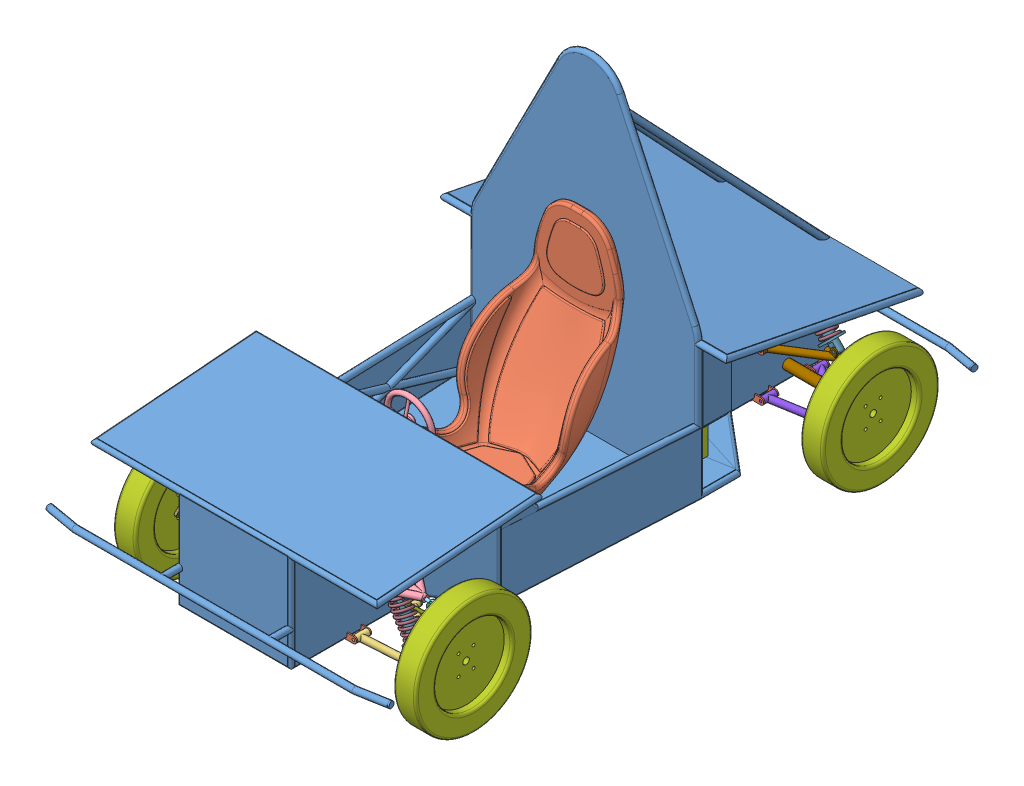
SolidWorks assembly Design report assembly, configuration Default. Lengths in mm.
Overall size (1371.98 1545.67 2400.3).
109 component instances, 30 part files, 125 mates.
Components (placement in the parent):
- RollCage with bodyworks-1: RollCage with bodyworks [Default<As Machined>] at (132.5653 649.3406 2655.1235) size (1371.98 1337.56 2400.3)
- wishbone mount-1: wishbone mount [Default] at (348.4653 649.3406 2441.8435) size (52.7 25.4 5)
- wishbone mount-2: wishbone mount [Default] at (348.4653 649.3406 2386.2135) size (52.7 25.4 5)
- wishbone mount-3: wishbone mount [Default] at (348.4653 649.3406 2238.6435) size (52.7 25.4 5)
- wishbone mount-4: wishbone mount [Default] at (348.4653 649.3406 2183.0135) size (52.7 25.4 5)
- wishbone mount-5: wishbone mount [Default] at (348.4653 830.0606 2441.8435) size (52.7 25.4 5)
- wishbone mount-6: wishbone mount [Default] at (348.4653 830.0606 2386.2135) size (52.7 25.4 5)
- wishbone mount-7: wishbone mount [Default] at (348.4653 830.0606 2238.6435) size (52.7 25.4 5)
- wishbone mount-8: wishbone mount [Default] at (348.4653 830.0606 2183.0135) size (52.7 25.4 5)
- wishbone mount-9: wishbone mount [Default] at (-83.3347 649.3406 2441.8435) x (-1 0 0) z (0 0 1) size (52.7 25.4 5)
- wishbone mount-10: wishbone mount [Default] at (-83.3347 649.3406 2183.0135) x (-1 0 0) z (0 0 1) size (52.7 25.4 5)
- wishbone mount-11: wishbone mount [Default] at (-83.3347 649.3406 2238.6435) x (-1 0 0) z (0 0 1) size (52.7 25.4 5)
- wishbone mount-12: wishbone mount [Default] at (-83.3347 649.3406 2386.2135) x (-1 0 0) z (0 0 1) size (52.7 25.4 5)
- wishbone mount-13: wishbone mount [Default] at (348.4653 830.0606 2441.8435) size (52.7 25.4 5)
- wishbone mount-14: wishbone mount [Default] at (-83.3347 830.0606 2441.8435) x (-1 0 0) z (0 0 1) size (52.7 25.4 5)
- wishbone mount-15: wishbone mount [Default] at (348.4653 830.0606 2386.2135) size (52.7 25.4 5)
- wishbone mount-16: wishbone mount [Default] at (-83.3347 830.0606 2386.2135) x (-1 0 0) z (0 0 1) size (52.7 25.4 5)
- wishbone mount-17: wishbone mount [Default] at (348.4653 830.0606 2238.6435) size (52.7 25.4 5)
- wishbone mount-18: wishbone mount [Default] at (-83.3347 830.0606 2238.6435) x (-1 0 0) z (0 0 1) size (52.7 25.4 5)
- wishbone mount-19: wishbone mount [Default] at (348.4653 830.0606 2183.0135) size (52.7 25.4 5)
- wishbone mount-20: wishbone mount [Default] at (-83.3347 830.0606 2183.0135) x (-1 0 0) z (0 0 1) size (52.7 25.4 5)
- wishbone mount-21: wishbone mount [Default] at (335.7653 649.3406 800.9235) size (52.7 25.4 5)
- wishbone mount-22: wishbone mount [Default] at (335.7653 649.3406 745.2935) size (52.7 25.4 5)
- wishbone mount-23: wishbone mount [Default] at (335.7653 649.3406 597.7235) size (52.7 25.4 5)
- wishbone mount-24: wishbone mount [Default] at (335.7653 649.3406 542.0935) size (52.7 25.4 5)
- wishbone mount-25: wishbone mount [Default] at (335.7653 823.0306 800.9235) size (52.7 25.4 5)
- wishbone mount-26: wishbone mount [Default] at (335.7653 823.0306 745.2935) size (52.7 25.4 5)
- wishbone mount-27: wishbone mount [Default] at (335.7653 823.0306 597.7235) size (52.7 25.4 5)
- wishbone mount-28: wishbone mount [Default] at (335.7653 823.0306 542.0935) size (52.7 25.4 5)
- wishbone mount-29: wishbone mount [Default] at (335.7653 823.0306 800.9235) size (52.7 25.4 5)
- wishbone mount-30: wishbone mount [Default] at (-70.6347 649.3406 800.9235) x (-1 0 0) z (0 0 1) size (52.7 25.4 5)
- wishbone mount-31: wishbone mount [Default] at (-70.6347 823.0306 800.9235) x (-1 0 0) z (0 0 1) size (52.7 25.4 5)
- wishbone mount-32: wishbone mount [Default] at (335.7653 823.0306 745.2935) size (52.7 25.4 5)
- wishbone mount-33: wishbone mount [Default] at (-70.6347 649.3406 745.2935) x (-1 0 0) z (0 0 1) size (52.7 25.4 5)
- wishbone mount-34: wishbone mount [Default] at (-70.6347 823.0306 745.2935) x (-1 0 0) z (0 0 1) size (52.7 25.4 5)
- wishbone mount-35: wishbone mount [Default] at (335.7653 823.0306 597.7235) size (52.7 25.4 5)
- wishbone mount-36: wishbone mount [Default] at (-70.6347 649.3406 597.7235) x (-1 0 0) z (0 0 1) size (52.7 25.4 5)
- wishbone mount-37: wishbone mount [Default] at (-70.6347 823.0306 597.7235) x (-1 0 0) z (0 0 1) size (52.7 25.4 5)
- wishbone mount-38: wishbone mount [Default] at (335.7653 823.0306 542.0935) size (52.7 25.4 5)
- wishbone mount-39: wishbone mount [Default] at (-70.6347 649.3406 542.0935) x (-1 0 0) z (0 0 1) size (52.7 25.4 5)
- wishbone mount-40: wishbone mount [Default] at (-70.6347 823.0306 542.0935) x (-1 0 0) z (0 0 1) size (52.7 25.4 5)
- front lower left (2)-1: front lower left (2) [Default<As Machined>] at (619.6175 543.0238 2314.8435) x (-0.90851 0.417863 0) z (0 0 -1) size (234.82 48.1 264)
- front upper (symmetrical) (1)-1: front upper (symmetrical) (1) [Default<As Machined>] at (580.2917 799.5352 2314.8435) x (-0.987574 0.157153 0) z (0 0 -1) size (172.65 25.4 264)
- heim joint-1: heim joint [Default<As Machined>] at (619.5978 543.0329 2314.6117) x (-0.90851 0.417863 0) z (-0.417863 -0.90851 0) size (68.82 35 36.03)
- heim joint-2: heim joint [Default<As Machined>] at (580.2702 799.5386 2314.6117) x (-0.987574 0.157153 0) z (0.157153 0.987574 0) size (68.82 35 36.03)
- Part2^Design report assembly-1: Part2^Design report assembly [Default] at origin (virtual)
- front left hub assly-1: front left hub assly [Default] at (1167.019 46.7863 2461.5796) x (-1 0 0) z (0 0 -1) size (116.83 286.51 162.89)
- tyre-1: tyre [Default] at (694.5978 670.0329 2314.6187) size (90 466.8 466.8)
- rear lower arm-1: rear lower arm [Default<As Machined>] at (606.6135 573.209 673.9235) x (-0.949688 0.313198 0) z (0 0 -1) size (221.49 25.4 264)
- rear upper arm-1: rear upper arm [Default<As Machined>] at (606.6135 827.209 673.9235) x (-0.999836 -0.018097 0) z (0 0 -1) size (209.3 48.1 264)
- heim joint-3: heim joint [Default<As Machined>] at (606.6135 573.209 673.9235) x (-0.949688 0.313198 0) z (0.313198 0.949688 0) size (68.82 35 36.03)
- heim joint-4: heim joint [Default<As Machined>] at (606.6135 827.209 673.9235) x (-0.999836 -0.018097 0) z (-0.018097 0.999836 0) size (68.82 35 36.03)
- rear hub assly-1: rear hub assly [Default] at (563.1926 752.076 736.7282) x (-1 0 0) z (0 0 -1) size (80 284 93.61)
- tyre-2: tyre [Default] at (681.6135 700.209 673.9235) size (90 466.8 466.8)
- tyre-4: tyre [Default] at (-416.4829 700.209 673.9235) x (-1 0 0) z (0 0 -1) size (90 466.8 466.8)
- heim joint-7: heim joint [Default<As Machined>] at (-341.4829 827.209 673.9235) x (0.999836 -0.018097 0) z (-0.018097 -0.999836 0) size (68.82 35 36.03)
- heim joint-8: heim joint [Default<As Machined>] at (-341.4829 573.209 673.9235) x (0.949688 0.313198 0) z (0.313198 -0.949688 0) size (68.82 35 36.03)
- rear lower arm-2: rear lower arm [Default<As Machined>] at (-341.4829 573.209 673.9235) x (0.949688 0.313198 0) z (0 0 1) size (221.49 25.4 264)
- wishbone mount-41: wishbone mount [Default] at (348.4653 830.0606 2327.5435) size (52.7 25.4 5)
- wishbone mount-42: wishbone mount [Default] at (348.4653 830.0606 2297.1435) size (52.7 25.4 5)
- rear hub assly-2: rear hub assly [Default] at (-298.062 752.076 611.1187) size (80 284 93.61)
- front lower left (2)-4: front lower left (2) [Default<As Machined>] at (-350.581 534.9128 2314.8435) x (0.893159 0.449742 0) z (0 0 1) size (234.82 48.1 264)
- front upper (symmetrical) (1)-4: front upper (symmetrical) (1) [Default<As Machined>] at (-313.1674 788.918 2314.8435) x (0.97731 0.211814 0) z (0 0 1) size (172.65 25.4 264)
- heim joint-9: heim joint [Default<As Machined>] at (-313.1462 788.9226 2315.0753) x (0.97731 0.211814 0) z (-0.211814 0.97731 0) size (68.82 35 36.03)
- heim joint-10: heim joint [Default<As Machined>] at (-350.5616 534.9226 2315.0753) x (0.893159 0.449742 0) z (-0.449742 0.893159 0) size (68.82 35 36.03)
- Fronnt knucle right-1: Fronnt knucle right [Default] at (-350.5616 661.9226 2315.0753) size (69.92 284 150.17)
- Wheel hub-1: Wheel hub [Default] at (-413.0616 661.9226 2315.0753) size (80 83.75 93.61)
- tyre-5: tyre [Default] at (-425.5616 661.9226 2315.0753) size (90 466.8 466.8)
- Shock Absorber-1: Shock Absorber [Default] at (700.6589 753.6025 2357.8386) x (0 0 1) z (-0.845028 -0.534723 0) size (86.36 285.25 86.36)
  - spring-1: spring [Default] at (-42.9952 9.8146 223.0067) size (71.8 203.64 70)
  - spring mount-1: spring mount [Default] at (-42.9952 101.6292 223.0067) x (1 0 0) z (0 1 0) size (86.36 86.36 285.92)
- wishbone mount-43: wishbone mount [Default] at (-83.3347 830.0606 2327.5435) x (-1 0 0) z (0 0 1) size (52.7 25.4 5)
- wishbone mount-44: wishbone mount [Default] at (-83.3347 830.0606 2297.1435) x (-1 0 0) z (0 0 1) size (52.7 25.4 5)
- Shock Absorber-2: Shock Absorber [Default] at (-436.2564 746.0193 2271.8483) x (0 0 -1) z (0.853187 -0.521605 0) size (86.36 285.25 86.36)
  - spring-1: spring [Default] at (-42.9952 9.8146 223.0067) size (71.8 203.64 70)
  - spring mount-1: spring mount [Default] at (-42.9952 101.6292 223.0067) x (1 0 0) z (0 1 0) size (86.36 86.36 285.92)
- Shock Absorber-3: Shock Absorber [Default] at (691.0322 1024.2094 714.4186) x (0 0 1) z (-0.719069 -0.694939 0) size (86.36 285.25 86.36)
  - spring-1: spring [Default] at (-42.9952 9.8146 223.0067) size (71.8 203.64 70)
  - spring mount-1: spring mount [Default] at (-42.9952 101.6292 223.0067) x (1 0 0) z (0 1 0) size (86.36 86.36 285.92)
- wishbone mount-45: wishbone mount [Default] at (335.7653 1030.3406 653.7235) size (52.7 25.4 5)
- wishbone mount-46: wishbone mount [Default] at (335.7653 1030.3406 684.1235) size (52.7 25.4 5)
- wishbone mount-47: wishbone mount [Default] at (-70.6347 1030.3406 653.7235) x (-1 0 0) z (0 0 1) size (52.7 25.4 5)
- wishbone mount-48: wishbone mount [Default] at (-70.6347 1030.3406 684.1235) x (-1 0 0) z (0 0 1) size (52.7 25.4 5)
- rear upper arm-3: rear upper arm [Default<As Machined>] at (-341.4829 827.209 674.0935) x (0.999836 -0.018097 0) z (0 0 1) size (209.3 48.1 264)
- Shock Absorber-5: Shock Absorber [Default] at (-421.5818 1027.5905 633.5983) x (0 0 -1) z (0.701897 -0.712278 0) size (86.36 285.25 86.36)
  - spring-1: spring [Default] at (-42.9952 9.8146 223.0067) size (71.8 203.64 70)
  - spring mount-1: spring mount [Default] at (-42.9952 101.6292 223.0067) x (1 0 0) z (0 1 0) size (86.36 86.36 285.92)
- rack spur rectangular_am-1: rack spur rectangular_am [Metric - Rack-spur - rectangular 2M 20PA 12FW 20PH 150L---SAll] at (57.5653 672.5329 2251.5235) size (150 22 12)
- heim joint-11: heim joint [Default<As Machined>] at (610.0174 682.5329 2245.3287) x (-1 0 0) z (0 0 -1) size (68.82 35 36.03)
- steering tie rod-1: steering tie rod [Default] at (383.3924 682.5329 2245.3287) x (1 0 0) z (0 -1 0) size (351.65 12 12)
- heim joint-13: heim joint [Default<As Machined>] at (-341.8073 671.9226 2246.2421) size (68.82 35 36.03)
- steering tie rod-3: steering tie rod [Default] at (-115.1823 671.9226 2246.2421) size (351.65 12 12)
- spur_gear_am-1: spur_gear_am [Metric - Spur gear 2M 20T 20PA 12FW ---S20N75H50L10N] at (132.5653 712.0329 2251.5235) x (0 0 -1) z (1 0 0) size (12 43.61 43.61)
- u-1: u [Default] at (132.5653 712.0329 2226.5235) x (0.999993 -0.003775 0) z (0.003775 0.999993 0) size (40 50 15)
- u center-1: u center [Default] at (132.5653 712.0329 2211.5235) x (0.003493 0.925367 -0.379057) z (-0.001431 -0.379054 -0.925373) size (10 20 20)
- u-2: u [Default] at (132.5653 725.9135 2205.8377) x (-0.001431 -0.379054 -0.925373) z (-0.999999 0.000542 0.001324) size (40 50 15)
- bucket seat-1: bucket seat [Default] at (132.5653 664.5806 1547.9516) x (0 0 1) z (-1 0 0) size (798.27 803.12 506.06)
- usb 204-2: usb 204 [Default] at (105.5364 1003.7258 1973.529) x (-1 0 0) z (0 -0.079745 0.996815) size (127 66.6 31)
- Steering wheel-1: Steering wheel [Default] at (132.5653 1041.9738 1964.7237) x (1 0 0) z (0 0.996815 0.079745) size (197.8 35 197.8)
- steering mount rod-1: steering mount rod [Default] at (132.5653 1037.9546 2014.9632) x (0 0.079745 -0.996815) z (0 -0.996815 -0.079745) size (50.8 10 10)
- u-3: u [Default] at (132.5653 1033.9354 2065.2027) x (0.982137 0.187568 0.015005) z (0.188167 -0.979009 -0.078321) size (40 50 15)
- u center-2: u center [Default] at (132.5653 1032.7393 2080.1549) x (-0.167258 0.906755 -0.387067) z (-0.086208 0.377643 0.921929) size (10 20 20)
- u-4: u [Default] at (132.5653 1018.8586 2085.8407) x (0.086208 -0.377643 -0.921929) z (0.996277 0.032677 0.079774) size (40 50 15)
- steering rod-1: steering rod [Default] at (132.5653 881.654 2142.0428) x (0 -0.925374 0.379054) z (-0.379054 0.350767 0.856318) size (286.6 10 10)
- Battery-1: Battery [Default] at (132.5653 664.5806 1179.3835) size (685.8 350 127)
- Motor-1: Motor [Default] at (132.5653 728.0806 1001.5835) size (203.2 127 127)
- rear axle shaft-1: rear axle shaft [Default] at (132.5635 700.209 673.9235) x (1 0 0) z (0 0.189773 0.981828) size (913.1 38.1 38.1)
- sporket-3: sporket [Metric - Spur gear 3M 105T 14.5PA 12FW ---S105N75H50L38N] at (241.5653 700.209 673.9235) size (12 320.96 320.99)
- pinion-1: pinion [Metric - Spur gear 2M 21T 20PA 12FW ---S21N75H50L24N] at (241.5653 728.0806 1001.5835) size (12 45.82 45.94)
Mates (geometry in assembly coordinates):
- Concentric1: concentric anti-aligned: cylinder of RollCage with bodyworks-1 through (348.4653 649.3406 2020.1235) axis (0 0 1) radius 12.7; cylinder of wishbone mount-1 through (348.4653 649.3406 2446.8435) axis (0 0 -1) radius 12.7
- Coincident2: coincident aligned: plane of RollCage with bodyworks-1 through (132.5653 649.3406 2655.1235) normal (0 1 0); plane of wishbone mount-1 through (348.4653 649.3406 2441.8435) normal (0 1 0)
- Distance1: distance = 223.52 mm aligned: plane of wishbone mount-1 through (348.4653 649.3406 2446.8435) normal (0 0 1); plane of RollCage with bodyworks-1 through (132.5653 649.3406 2670.3635) normal (0 0 1)
- Concentric2: concentric aligned: cylinder of RollCage with bodyworks-1 through (335.7653 649.3406 1258.1235) axis (0 0 -1) radius 12.7; cylinder of wishbone mount-21 through (335.7653 649.3406 805.9235) axis (0 0 -1) radius 12.7
- Distance2: distance = 132 mm: plane of wishbone mount-21 through (335.7653 649.3406 805.9235) normal (0 0 1); line of RollCage with bodyworks-1 through (665.9653 649.3406 673.9235) axis (-1 0 0)
- Coincident5: coincident aligned: plane of RollCage with bodyworks-1 through (132.5653 649.3406 2655.1235) normal (0 1 0); plane of wishbone mount-21 through (335.7653 649.3406 800.9235) normal (0 1 0)
- Coincident6: coincident anti-aligned: plane of wishbone mount-1 through (348.4653 649.3406 2441.8435) normal (0 0 -1); plane of front lower left (2)-1 through (388.4653 649.3406 2441.8435) normal (0 0 1)
- Concentric3: concentric aligned: cylinder of wishbone mount-1 through (388.4653 649.3406 2446.8435) axis (0 0 -1) radius 5; cylinder of front lower left (2)-1 through (388.4653 649.3406 2446.8435) axis (0 0 -1) radius 5
- Coincident7: coincident anti-aligned: plane of wishbone mount-5 through (348.4653 830.0606 2441.8435) normal (0 0 -1); plane of front upper (symmetrical) (1)-1 through (388.4653 830.0606 2441.8435) normal (0 0 1)
- Concentric4: concentric aligned: cylinder of wishbone mount-5 through (388.4653 830.0606 2446.8435) axis (0 0 -1) radius 5; cylinder of front upper (symmetrical) (1)-1 through (388.4653 830.0606 2446.8435) axis (0 0 -1) radius 5
- Concentric6: concentric aligned: cylinder of front lower left (2)-1 through (588.4686 557.3506 2314.6117) axis (-0.90851 0.417863 0) radius 6; cylinder of heim joint-1 through (610.4979 547.2183 2314.6117) axis (-0.90851 0.417863 0) radius 6
- Coincident8: coincident: point of front lower left (2)-1; point of heim joint-1
- Parallel1: parallel aligned: plane of front lower left (2)-1 through (619.6175 543.0238 2314.8435) normal (0 0 -1); plane of heim joint-1 through (619.5978 543.0329 2314.6117) normal (0 0 -1)
- Coincident10: coincident anti-aligned: circle of front upper (symmetrical) (1)-1; cylinder of heim joint-2 through (570.3784 801.1127 2314.6117) axis (-0.987574 0.157153 0) radius 6
- Coincident11: coincident: point of front upper (symmetrical) (1)-1; point of heim joint-2
- Parallel3: parallel anti-aligned: plane of front upper (symmetrical) (1)-1 through (580.2917 799.5352 2314.8435) normal (0 0 -1); plane of heim joint-2 through (580.2702 799.5386 2314.6117) normal (0 0 1)
- Concentric10: concentric anti-aligned: cylinder of heim joint-1 through (619.5978 543.0329 2332.1117) axis (0 0 -1) radius 6; cylinder of front left hub assly-1 through (619.5978 543.0329 2297.1257) axis (0 0 1) radius 5
- Coincident16: coincident aligned: plane of heim joint-1 through (619.5978 543.0329 2332.1117) normal (0 0 1); plane of front left hub assly-1 through (591.0547 635.0329 2332.1117) normal (0 0 1)
- Concentric11: concentric anti-aligned: cylinder of heim joint-2 through (580.2702 799.5386 2297.1117) axis (0 0 1) radius 6; cylinder of front left hub assly-1 through (580.2702 799.5386 2332.1117) axis (0 0 -1) radius 5
- Coincident17: coincident anti-aligned: plane of front left hub assly-1 through (682.0978 645.179 2315.3318) normal (1 0 0); plane of tyre-1 through (682.0978 670.0329 2314.6187) normal (-1 0 0)
- Concentric12: concentric aligned: cylinder of front left hub assly-1 through (672.0978 670.0329 2314.6187) axis (1 0 0) radius 10; cylinder of tyre-1 through (649.5978 670.0329 2314.6187) axis (1 0 0) radius 13
- Parallel4: parallel aligned: plane of RollCage with bodyworks-1 through (132.5653 649.3406 2655.1235) normal (0 1 0); plane of tyre-1 through (694.5978 670.0329 2314.6187) normal (0 1 0)
- Coincident19: coincident anti-aligned: plane of wishbone mount-21 through (335.7653 649.3406 800.9235) normal (0 0 -1); plane of rear lower arm-1 through (375.7653 649.3406 800.9235) normal (0 0 1)
- Concentric13: concentric aligned: cylinder of wishbone mount-21 through (375.7653 649.3406 805.9235) axis (0 0 -1) radius 5; cylinder of rear lower arm-1 through (375.7653 649.3406 805.9235) axis (0 0 -1) radius 5
- Coincident20: coincident anti-aligned: plane of wishbone mount-29 through (335.7653 823.0306 800.9235) normal (0 0 -1); plane of rear upper arm-1 through (375.7653 823.0306 800.9235) normal (0 0 1)
- Concentric14: concentric aligned: cylinder of wishbone mount-29 through (375.7653 823.0306 805.9235) axis (0 0 -1) radius 5; cylinder of rear upper arm-1 through (375.7653 823.0306 805.9235) axis (0 0 -1) radius 5
- Concentric15: concentric anti-aligned: cylinder of rear lower arm-1 through (571.1996 584.8882 673.9235) axis (0.949688 -0.313198 0) radius 6; cylinder of heim joint-3 through (597.1011 576.3461 673.9235) axis (-0.949688 0.313198 0) radius 6
- Coincident21: coincident: point of rear lower arm-1; point of heim joint-3
- Coincident22: coincident anti-aligned: plane of rear lower arm-1 through (606.6135 573.209 673.9235) normal (0 0 -1); plane of heim joint-3 through (606.6135 573.209 673.9235) normal (0 0 1)
- Concentric16: concentric anti-aligned: cylinder of rear upper arm-1 through (569.3296 826.5341 673.9235) axis (0.999836 0.018097 0) radius 6; cylinder of heim joint-4 through (596.5988 827.0277 673.9235) axis (-0.999836 -0.018097 0) radius 6
- Coincident23: coincident: point of rear upper arm-1; point of heim joint-4
- Coincident24: coincident anti-aligned: plane of rear upper arm-1 through (606.6135 827.209 673.9235) normal (0 0 -1); plane of heim joint-4 through (606.6135 827.209 673.9235) normal (0 0 1)
- Concentric17: concentric aligned: cylinder of heim joint-3 through (606.6135 573.209 656.4235) axis (0 0 1) radius 6; cylinder of rear hub assly-1 through (606.6135 573.209 656.4235) axis (0 0 1) radius 5
- Coincident25: coincident aligned: plane of heim joint-3 through (606.6135 573.209 691.4235) normal (0 0 1); plane of rear hub assly-1 through (606.6135 573.209 691.4235) normal (0 0 1)
- Concentric18: concentric anti-aligned: cylinder of heim joint-4 through (606.6135 827.209 656.4235) axis (0 0 1) radius 6; cylinder of rear hub assly-1 through (606.6135 827.209 691.4235) axis (0 0 -1) radius 5
- Coincident26: coincident anti-aligned: plane of rear hub assly-1 through (669.1135 675.3551 674.6366) normal (1 0 0); plane of tyre-2 through (669.1135 700.209 673.9235) normal (-1 0 0)
- Concentric19: concentric aligned: cylinder of rear hub assly-1 through (659.1135 700.209 673.9235) axis (1 0 0) radius 10; cylinder of tyre-2 through (636.6135 700.209 673.9235) axis (1 0 0) radius 13
- Parallel5: parallel aligned: plane of RollCage with bodyworks-1 through (132.5653 649.3406 2655.1235) normal (0 1 0); plane of tyre-2 through (681.6135 700.209 673.9235) normal (0 1 0)
- Concentric20: concentric anti-aligned: cylinder of RollCage with bodyworks-1 through (348.4653 830.0606 2147.1235) axis (0 0 1) radius 12.7; cylinder of wishbone mount-41 through (348.4653 830.0606 2332.5435) axis (0 0 -1) radius 12.7
- Distance4: distance = 337.82 mm aligned: plane of wishbone mount-41 through (348.4653 830.0606 2332.5435) normal (0 0 1); plane of RollCage with bodyworks-1 through (132.5653 649.3406 2670.3635) normal (0 0 1)
- Parallel6: parallel aligned: plane of RollCage with bodyworks-1 through (132.5653 649.3406 2655.1235) normal (0 1 0); plane of wishbone mount-41 through (348.4653 830.0606 2327.5435) normal (0 1 0)
- Coincident31: coincident anti-aligned: plane of wishbone mount-9 through (-83.3347 649.3406 2441.8435) normal (0 0 -1); plane of front lower left (2)-4 through (-123.3347 649.3406 2441.8435) normal (0 0 1)
- Coincident32: coincident aligned: circle of wishbone mount-9; cylinder of front lower left (2)-4 through (-123.3347 649.3406 2386.0435) axis (0 0 1) radius 5
- Coincident33: coincident anti-aligned: plane of wishbone mount-14 through (-83.3347 830.0606 2441.8435) normal (0 0 -1); plane of front upper (symmetrical) (1)-4 through (-123.3347 830.0606 2441.8435) normal (0 0 1)
- Concentric21: concentric anti-aligned: cylinder of wishbone mount-14 through (-123.3347 830.0606 2446.8435) axis (0 0 -1) radius 5; cylinder of front upper (symmetrical) (1)-4 through (-123.3347 830.0606 2386.0435) axis (0 0 1) radius 5
- Concentric22: concentric aligned: cylinder of front lower left (2)-4 through (-319.9584 550.3325 2315.0753) axis (0.893159 0.449742 0) radius 6; cylinder of heim joint-10 through (-341.6155 539.4273 2315.0753) axis (0.893159 0.449742 0) radius 6
- Coincident35: coincident: point of front lower left (2)-4; point of heim joint-10
- Parallel7: parallel anti-aligned: plane of front lower left (2)-4 through (-350.581 534.9128 2314.8435) normal (0 0 1); plane of heim joint-10 through (-350.5616 534.9226 2315.0753) normal (0 0 -1)
- Coincident37: coincident anti-aligned: circle of front upper (symmetrical) (1)-4; cylinder of heim joint-9 through (-303.3572 791.0441 2315.0753) axis (0.97731 0.211814 0) radius 6
- Coincident38: coincident: point of front upper (symmetrical) (1)-4; point of heim joint-9
- Parallel8: parallel anti-aligned: plane of front upper (symmetrical) (1)-4 through (-313.1674 788.918 2314.8435) normal (0 0 1); plane of heim joint-9 through (-313.1462 788.9226 2315.0753) normal (0 0 -1)
- Concentric23: concentric aligned: cylinder of heim joint-10 through (-350.5616 534.9226 2332.5753) axis (0 0 -1) radius 6; cylinder of Fronnt knucle right-1 through (-350.5616 534.9226 2332.5753) axis (0 0 -1) radius 5
- Coincident40: coincident aligned: plane of heim joint-10 through (-350.5616 534.9226 2332.5753) normal (0 0 1); plane of Fronnt knucle right-1 through (-378.9603 661.9226 2332.5753) normal (0 0 1)
- Concentric24: concentric aligned: cylinder of heim joint-9 through (-313.1462 788.9226 2332.5753) axis (0 0 -1) radius 6; cylinder of Fronnt knucle right-1 through (-313.1462 788.9226 2332.5753) axis (0 0 -1) radius 5
- Concentric25: concentric aligned: cylinder of Fronnt knucle right-1 through (-333.0616 661.9226 2315.0753) axis (-1 0 0) radius 15; cylinder of Wheel hub-1 through (-333.0616 661.9226 2315.0753) axis (-1 0 0) radius 15
- Coincident41: coincident aligned: plane of Fronnt knucle right-1 through (-333.0616 661.9226 2315.0753) normal (1 0 0); plane of Wheel hub-1 through (-333.0616 661.9226 2315.0753) normal (1 0 0)
- Coincident42: coincident anti-aligned: plane of Wheel hub-1 through (-413.0616 637.0687 2314.3622) normal (-1 0 0); plane of tyre-5 through (-413.0616 661.9226 2315.0753) normal (1 0 0)
- Concentric26: concentric anti-aligned: cylinder of Wheel hub-1 through (-403.0616 661.9226 2315.0753) axis (-1 0 0) radius 10; cylinder of tyre-5 through (-470.5616 661.9226 2315.0753) axis (1 0 0) radius 13
- Parallel9: parallel aligned: plane of RollCage with bodyworks-1 through (132.5653 649.3406 2655.1235) normal (0 1 0); plane of tyre-5 through (-425.5616 661.9226 2315.0753) normal (0 1 0)
- Concentric27: concentric anti-aligned: cylinder of front lower left (2)-1 through (527.3372 610.4535 2332.5435) axis (0 0 -1) radius 6; cylinder of Shock Absorber-1/spring mount-1 through (527.3372 610.4535 2297.1435) axis (0 0 1) radius 6
- Coincident44: coincident aligned: plane of front lower left (2)-1 through (527.3372 610.4535 2332.5435) normal (0 0 1); plane of Shock Absorber-1/spring mount-1 through (527.3372 610.4535 2332.5435) normal (0 0 1)
- Concentric33: concentric anti-aligned: cylinder of front lower left (2)-4 through (-260.7439 605.5649 2327.5435) axis (0 0 1) radius 6; cylinder of Shock Absorber-2/spring mount-1 through (-260.7439 605.5649 2332.5435) axis (0 0 -1) radius 6
- Coincident45: coincident: point of front lower left (2)-4; plane of Shock Absorber-2/spring mount-1 through (-260.7439 605.5649 2332.5435) normal (0 0 1)
- Parallel14: parallel aligned: cylinder of wishbone mount-43 through (-123.3347 830.0606 2332.5435) axis (0 0 -1) radius 5; cylinder of Shock Absorber-2/spring mount-1 through (-125.2153 827.2485 2332.5435) axis (0 0 -1) radius 5
- Concentric35: concentric anti-aligned: cylinder of rear upper arm-1 through (550.3318 848.894 663.7235) axis (0 0 -1) radius 6; cylinder of Shock Absorber-3/spring mount-1 through (550.3318 848.894 653.7235) axis (0 0 1) radius 6
- Coincident48: coincident aligned: plane of rear upper arm-1 through (550.3318 848.894 689.1235) normal (0 0 1); plane of Shock Absorber-3/spring mount-1 through (550.3318 848.894 689.1235) normal (0 0 1)
- Concentric36: concentric anti-aligned: cylinder of RollCage with bodyworks-1 through (335.7653 1030.3406 496.1235) axis (0 0 1) radius 12.7; cylinder of wishbone mount-45 through (335.7653 1030.3406 658.7235) axis (0 0 -1) radius 12.7
- Distance5: distance = 12.7 mm: line of wishbone mount-45 through (375.7653 1043.0406 658.7235) axis (-1 0 0); line of Shock Absorber-3/spring mount-1 through (369.7662 1035.7295 671.4235) axis (0.694939 -0.719069 0)
- Parallel16: parallel aligned: plane of RollCage with bodyworks-1 through (132.5653 649.3406 2655.1235) normal (0 1 0); plane of wishbone mount-45 through (335.7653 1030.3406 653.7235) normal (0 1 0)
- Coincident51: coincident anti-aligned: plane of wishbone mount-40 through (-70.6347 823.0306 547.0935) normal (0 0 1); plane of rear upper arm-3 through (-110.6347 823.0306 547.0935) normal (0 0 -1)
- Concentric37: concentric anti-aligned: cylinder of wishbone mount-40 through (-110.6347 823.0306 547.0935) axis (0 0 -1) radius 5; cylinder of rear upper arm-3 through (-110.6347 823.0306 542.0935) axis (0 0 1) radius 5
- Parallel17: parallel anti-aligned: cylinder of heim joint-7 through (-331.4683 827.0277 673.9235) axis (0.999836 -0.018097 0) radius 6; cylinder of rear upper arm-3 through (-304.199 826.5341 674.0935) axis (-0.999836 0.018097 0) radius 6
- Concentric39: concentric anti-aligned: cylinder of rear upper arm-3 through (-285.2012 848.894 658.8935) axis (0 0 1) radius 6; cylinder of Shock Absorber-5/spring mount-1 through (-285.2012 848.894 694.2935) axis (0 0 -1) radius 6
- Coincident53: coincident aligned: plane of rear upper arm-3 through (-285.2012 848.894 658.8935) normal (0 0 -1); plane of Shock Absorber-5/spring mount-1 through (-285.2012 848.894 658.8935) normal (0 0 -1)
- Distance8: distance = 48 mm aligned: plane of rack spur rectangular_am-1 through (57.5653 672.5329 2251.5235) normal (0 0 1)
- Concentric41: concentric aligned: cylinder of heim joint-11 through (600.0011 682.5329 2245.3287) axis (-1 0 0) radius 6; cylinder of steering tie rod-1 through (559.2174 682.5329 2245.3287) axis (-1 0 0) radius 6
- Coincident68: coincident anti-aligned: plane of heim joint-11 through (559.2174 682.5329 2245.3287) normal (-1 0 0); plane of steering tie rod-1 through (559.2174 682.5329 2245.3287) normal (1 0 0)
- Concentric42: concentric anti-aligned: cylinder of front left hub assly-1 through (610.0174 675.0329 2245.3287) axis (0 -1 0) radius 5; cylinder of heim joint-11 through (610.0174 665.0329 2245.3287) axis (0 1 0) radius 6
- Coincident70: coincident anti-aligned: plane of front left hub assly-1 through (600.437 675.0329 2211.0387) normal (0 1 0); plane of heim joint-11 through (610.0174 675.0329 2251.3287) normal (0 -1 0)
- Distance11: distance = 10 mm anti-aligned: plane of rack spur rectangular_am-1 through (57.5653 672.5329 2251.5235) normal (0 1 0); plane of steering tie rod-1 through (383.3924 682.5329 2245.3287) normal (0 -1 0)
- Concentric43: concentric anti-aligned: cylinder of Fronnt knucle right-1 through (-341.8073 664.4226 2246.2421) axis (0 -1 0) radius 5; cylinder of heim joint-13 through (-341.8073 654.4226 2246.2421) axis (0 1 0) radius 6
- Coincident72: coincident anti-aligned: plane of Fronnt knucle right-1 through (-333.0531 664.4226 2214.909) normal (0 1 0); plane of heim joint-13 through (-341.8073 664.4226 2240.2421) normal (0 -1 0)
- Coincident73: coincident anti-aligned: plane of heim joint-13 through (-291.0073 671.9226 2246.2421) normal (1 0 0); plane of steering tie rod-3 through (-291.0073 671.9226 2246.2421) normal (-1 0 0)
- Concentric44: concentric anti-aligned: cylinder of heim joint-13 through (-331.7911 671.9226 2246.2421) axis (1 0 0) radius 6; cylinder of steering tie rod-3 through (60.6427 671.9226 2246.2421) axis (-1 0 0) radius 6
- Distance12: distance = 75 mm aligned: plane of rack spur rectangular_am-1 through (57.5653 672.5329 2251.5235) normal (1 0 0); plane of RollCage with bodyworks-1 through (132.5653 649.3406 2655.1235) normal (1 0 0)
- Coincident76: coincident aligned: plane of rack spur rectangular_am-1 through (57.5653 694.5329 2251.5235) normal (0 0 1); plane of spur gear_am-1 through (132.5653 712.0329 2251.5235) normal (0 0 1)
- Coincident77: coincident aligned: plane of RollCage with bodyworks-1 through (132.5653 649.3406 2655.1235) normal (1 0 0); plane of spur gear_am-1 through (132.5653 712.0329 2251.5235) normal (1 0 0)
- Concentric46: concentric anti-aligned: cylinder of spur gear_am-1 through (132.5653 712.0329 2201.5234) axis (0 0 1) radius 5; cylinder of u-1 through (132.5653 712.0329 2251.5235) axis (0 0 -1) radius 5
- Coincident78: coincident aligned: plane of spur gear_am-1 through (132.5653 712.0329 2251.5235) normal (0 0 1); plane of u-1 through (132.5653 712.0329 2251.5235) normal (0 0 1)
- Coincident79: coincident aligned: circle of u-1; plane of u center-1 through (142.5652 711.9951 2211.5235) normal (0.999993 -0.003775 0)
- Concentric47: concentric anti-aligned: cylinder of u-1 through (98.4234 712.1618 2211.5235) axis (0.999993 -0.003775 0) radius 5; cylinder of u center-1 through (142.5652 711.9951 2211.5235) axis (-0.999993 0.003775 0) radius 5
- Concentric48: concentric anti-aligned: cylinder of u center-1 through (132.551 708.2424 2202.2697) axis (0.001431 0.379054 0.925373) radius 5; cylinder of u-2 through (132.6142 724.9746 2243.1177) axis (-0.001431 -0.379054 -0.925373) radius 5
- Coincident80: coincident aligned: plane of u center-1 through (132.5796 715.8234 2220.7772) normal (0.001431 0.379054 0.925373); circle of u-2
- Tangent3: tangent anti-aligned: plane of rack spur rectangular_am-1 through (133.8254 690.0329 2239.5235) normal (0 1 0); cylinder of spur gear_am-1 through (132.5653 712.0329 2261.5235) axis (0 0 1) radius 22
- Coincident81: coincident anti-aligned: plane of RollCage with bodyworks-1 through (132.5653 649.3406 2655.1235) normal (1 0 0); plane of bucket seat-1 through (132.5653 664.5806 1547.9516) normal (-1 0 0)
- Coincident82: coincident anti-aligned: plane of RollCage with bodyworks-1 through (450.0653 1180.3386 1270.8235) normal (0 0 1); plane of bucket seat-1 through (132.5653 1645.2042 1270.8235) normal (0 0 -1)
- Coincident83: coincident anti-aligned: plane of RollCage with bodyworks-1 through (132.5653 664.5806 2655.1235) normal (0 1 0); plane of bucket seat-1 through (132.5653 664.5806 1787.2736) normal (0 -1 0)
- Distance13: distance = 25.4 mm aligned: plane of RollCage with bodyworks-1 through (132.5653 1043.1092 2686.625) normal (0 0.996815 0.079745); plane of usb 204-2 through (196.5742 1070.0002 2031.9728) normal (0 0.996815 0.079745)
- Tangent4: tangent aligned: cylinder of RollCage with bodyworks-1 through (691.3653 1081.1406 2020.1235) axis (-1 0 0) radius 12.7; plane of usb 204-2 through (94.2653 1050.0639 2030.3779) normal (0 -0.079745 0.996815)
- Concentric49: concentric anti-aligned: cylinder of usb 204-2 through (132.5653 1033.6735 2068.4765) axis (0 0.079745 -0.996815) radius 5; cylinder of steering mount rod-1 through (132.5653 1039.9801 1989.6441) axis (0 -0.079745 0.996815) radius 5
- Concentric50: concentric anti-aligned: circle of usb 204-2; circle of steering mount rod-1
- Coincident86: coincident aligned: circle of usb 204-2; plane of steering mount rod-1 through (132.5653 1035.9291 2040.2823) normal (0 -0.079745 0.996815)
- Coincident87: coincident anti-aligned: plane of Steering wheel-1 through (142.5653 1039.9801 1989.6441) normal (0 -0.079745 0.996815); plane of steering mount rod-1 through (132.5653 1039.9801 1989.6441) normal (0 0.079745 -0.996815)
- Concentric52: concentric anti-aligned: cylinder of Steering wheel-1 through (132.5653 1044.7869 1929.5591) axis (0 0.079745 -0.996815) radius 10; cylinder of steering mount rod-1 through (132.5653 1039.9801 1989.6441) axis (0 -0.079745 0.996815) radius 5
- Coincident88: coincident anti-aligned: plane of steering mount rod-1 through (132.5653 1035.9291 2040.2823) normal (0 -0.079745 0.996815); plane of u-3 through (132.5653 1035.9291 2040.2823) normal (0 0.079745 -0.996815)
- Coincident89: coincident anti-aligned: circle of usb 204-2; cylinder of u-3 through (132.5653 1035.9291 2040.2823) axis (0 -0.079745 0.996815) radius 5
- Coincident90: coincident aligned: circle of u-3; circle of u center-2
- Coincident91: coincident aligned: plane of u center-2 through (131.7032 1036.5157 2089.3742) normal (-0.086208 0.377643 0.921929); circle of u-4
- Concentric53: concentric aligned: cylinder of u center-2 through (131.7032 1036.5157 2089.3742) axis (0.086208 -0.377643 -0.921929) radius 5; cylinder of u-4 through (129.622 1045.6328 2111.6315) axis (0.086208 -0.377643 -0.921929) radius 5
- Coincident92: coincident aligned: plane of RollCage with bodyworks-1 through (132.5653 649.3406 2655.1235) normal (1 0 0); plane of steering mount rod-1 through (132.5653 1037.9546 2014.9632) normal (1 0 0)
- Coincident94: coincident anti-aligned: plane of u-2 through (132.5653 749.0479 2196.3613) normal (0 0.925374 -0.379054); plane of steering rod-1 through (132.5653 749.0479 2196.3613) normal (0 -0.925374 0.379054)
- Concentric56: concentric anti-aligned: cylinder of u-2 through (132.5653 749.0479 2196.3613) axis (0 -0.925374 0.379054) radius 5; cylinder of steering rod-1 through (132.5653 749.0479 2196.3613) axis (0 0.925374 -0.379054) radius 5
- Concentric57: concentric aligned: cylinder of u-4 through (132.5653 995.7243 2095.3171) axis (0 0.925374 -0.379054) radius 5; cylinder of steering rod-1 through (132.5653 749.0479 2196.3613) axis (0 0.925374 -0.379054) radius 5
- Coincident95: coincident anti-aligned: plane of RollCage with bodyworks-1 through (132.5653 664.5806 2655.1235) normal (0 1 0); plane of Battery-1 through (132.5653 664.5806 1179.3835) normal (0 -1 0)
- Coincident96: coincident aligned: plane of RollCage with bodyworks-1 through (132.5653 649.3406 2655.1235) normal (1 0 0); plane of Battery-1 through (132.5653 664.5806 1179.3835) normal (1 0 0)
- Distance14: distance = 25.4 mm anti-aligned: plane of Battery-1 through (-210.3347 1014.5806 1242.8835) normal (0 0 1); plane of RollCage with bodyworks-1 through (450.0653 1180.3386 1268.2835) normal (0 0 -1)
- Coincident98: coincident aligned: plane of RollCage with bodyworks-1 through (132.5653 649.3406 2655.1235) normal (1 0 0); plane of Motor-1 through (132.5653 728.0806 1001.5835) normal (1 0 0)
- Coincident99: coincident anti-aligned: plane of RollCage with bodyworks-1 through (132.5653 664.5806 2655.1235) normal (0 1 0); plane of Motor-1 through (208.7653 664.5806 1055.0835) normal (0 -1 0)
- Distance15: distance = 50.8 mm anti-aligned: plane of Motor-1 through (208.7653 781.5806 1065.0835) normal (0 0 1); plane of Battery-1 through (-210.3347 1014.5806 1115.8835) normal (0 0 -1)
- Concentric58: concentric anti-aligned: cylinder of rear hub assly-1 through (659.1135 700.209 673.9235) axis (1 0 0) radius 10; cylinder of rear axle shaft-1 through (589.1135 700.209 673.9235) axis (-1 0 0) radius 19.05
- Coincident101: coincident anti-aligned: plane of rear hub assly-1 through (589.1135 700.209 673.9235) normal (-1 0 0); plane of rear axle shaft-1 through (589.1135 700.209 673.9235) normal (1 0 0)
- Concentric61: concentric aligned: cylinder of rear axle shaft-1 through (589.1135 700.209 673.9235) axis (-1 0 0) radius 19.05; cylinder of sporket-3 through (291.5653 700.209 673.9235) axis (-1 0 0) radius 19
- Distance16: distance = 6 mm aligned: plane of sporket-3 through (253.5653 700.209 673.9235) normal (1 0 0); plane of Motor-1 through (259.5653 728.0806 1001.5835) normal (1 0 0)
- Concentric62: concentric aligned: cylinder of Motor-1 through (259.5653 728.0806 1001.5835) axis (-1 0 0) radius 12.7; cylinder of pinion-1 through (291.5653 728.0806 1001.5835) axis (-1 0 0) radius 12
- Distance17: distance = 6 mm aligned: plane of pinion-1 through (253.5653 728.0806 1001.5835) normal (1 0 0); plane of Motor-1 through (259.5653 728.0806 1001.5835) normal (1 0 0)
